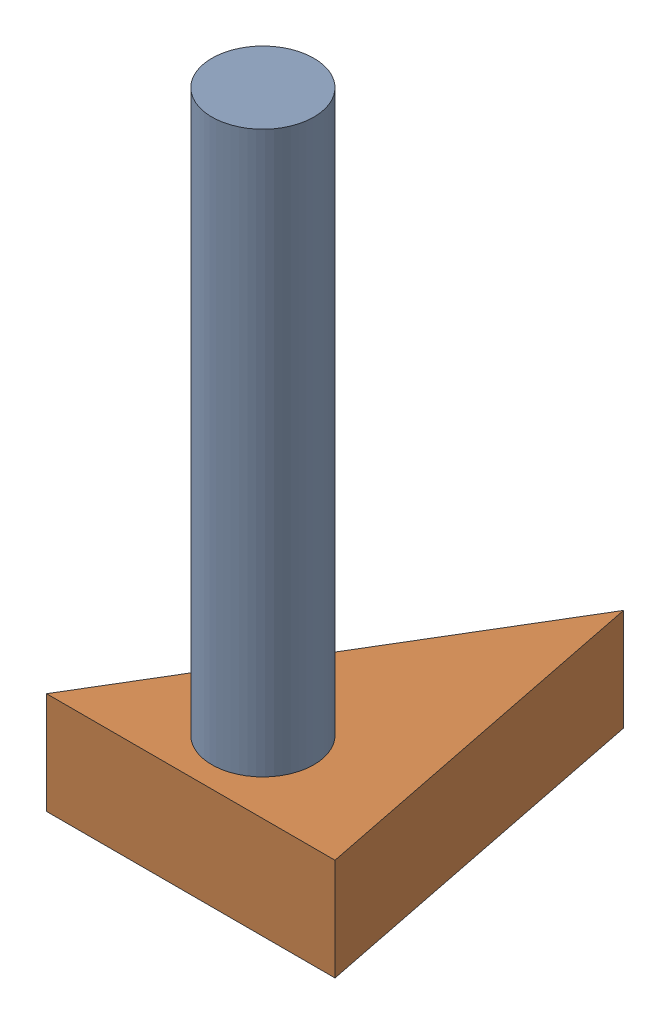
SolidWorks assembly Assem2, configuration Default. Lengths in mm.
Overall size (125.72 165.1 125.72).
2 component instances, 2 part files, 5 mates.
Components (placement in the parent):
- Part3-1: Part3 [Default] at (35.921 12.7 -17.9605) x (0.684961 0 -0.72858) z (0.72858 0 0.684961) size (25.4 152.4 25.4)
- Part4-1: Part4 [Default] x (0.707107 0 -0.707107) z (0.707107 0 0.707107) size (101.6 25.4 76.2)
Mates (geometry in assembly coordinates):
- Coincident1: coincident anti-aligned: plane of Part3-1 through (35.921 12.7 -17.9605) normal (0 -1 0); plane of Part4-1 through (35.921 12.7 -17.9605) normal (0 1 0)
- Concentric1: concentric anti-aligned: cylinder of Part3-1 through (35.921 165.1 -17.9605) axis (0 -1 0) radius 12.7; cylinder of Part4-1 through (35.921 12.7 -17.9605) axis (0 1 0) radius 12.7
- Coincident2: coincident: point of Part4-1
- Coincident3: coincident aligned: plane of Part4-1 through (0 25.4 0) normal (0 0 1)
- Coincident4: coincident anti-aligned: plane of Part4-1 through (0 0 0) normal (0 -1 0)
